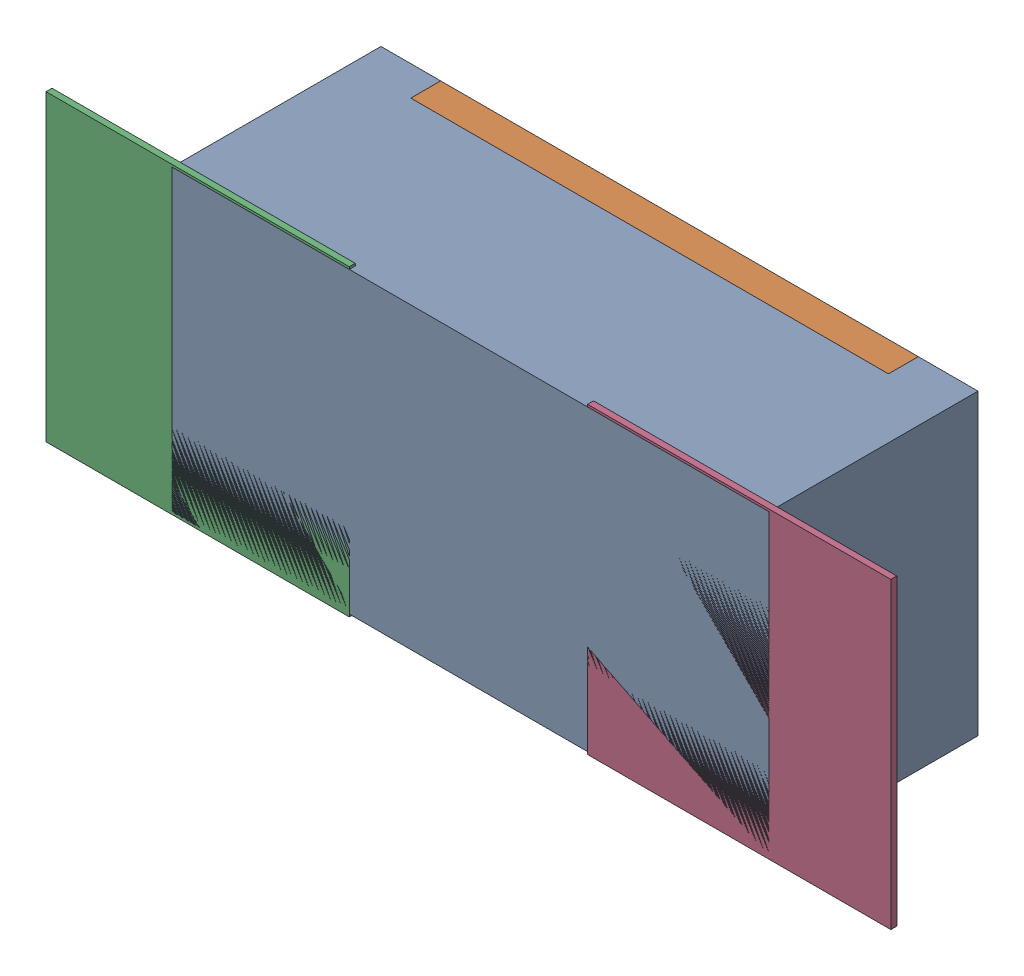
SolidWorks assembly R34, configuration Défaut. Lengths in mm.
Overall size (1.42 0.51 0.35).
5 component instances, 2 part files, 0 mates.
Components (placement in the parent):
- R0402-1: R0402 [Défaut] at (20.4655 -12.3611 -2.0818) x (1 0 0) z (0 0 -1) size (1 0.5 0.35)
- 6504207776-1: 6504207776 [Défaut] at (20.0085 -12.3612 -2.0918) size (0.51 0.51 0.01)
  - Extruded-1: Extruded [Défaut] at origin size (0.51 0.51 0.01)
- 6504207776-2: 6504207776 [Défaut] at (20.9155 -12.3612 -2.0918) size (0.51 0.51 0.01)
  - Extruded-1: Extruded [Défaut] at origin size (0.51 0.51 0.01)
